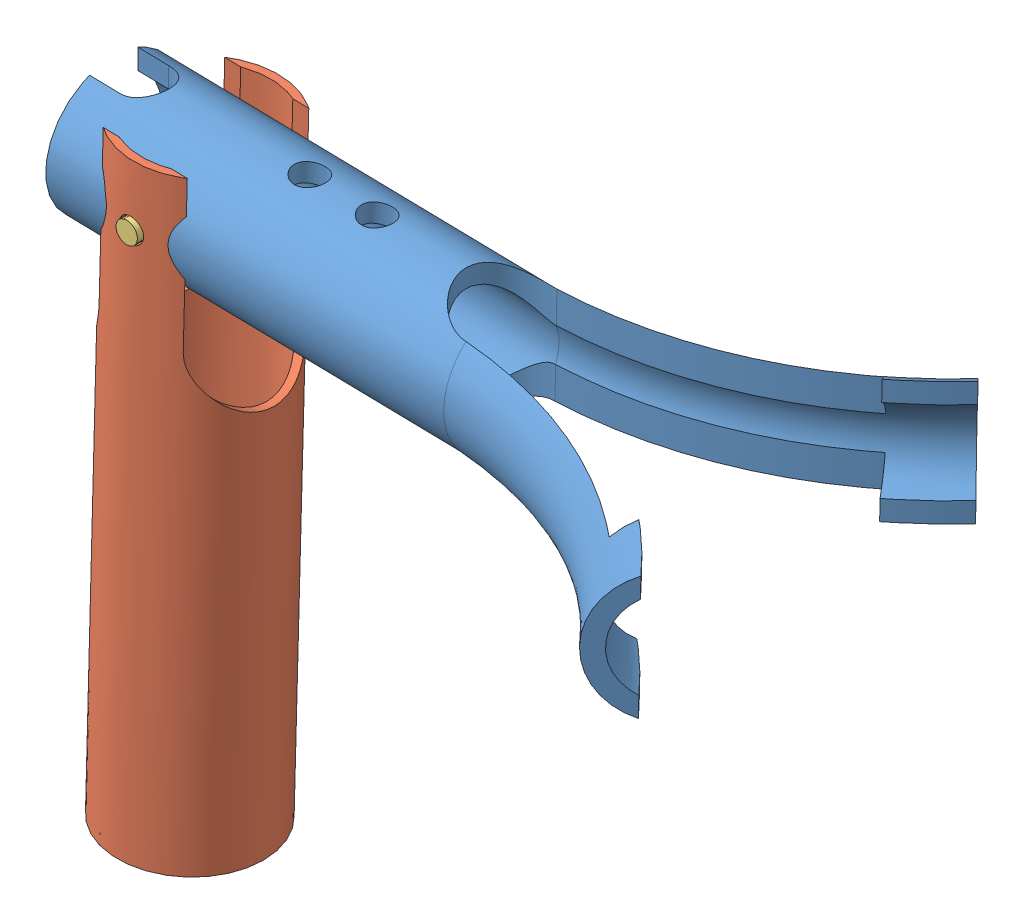
SolidWorks assembly pin joint assembly, configuration Default. Lengths in mm.
Overall size (19.69 24.55 21.3).
3 component instances, 3 part files, 8 mates.
Components (placement in the parent):
- tube-1: tube [Default] at (8.8823 0.7926 18.0506) x (0 0 -1) z (-0.019735 -0.999805 0) size (6.49 11.36 2.18)
- stainless steel tube_pin joint-1: stainless steel tube_pin joint [Default] at (10.4086 1.7627 18.0506) x (-0.026615 -0.999646 0) z (0.999646 -0.026615 0) size (11 2.41 2.41)
- pin-1: pin [Default] at (10.382 0.763 16.7795) x (0 0 1) z (-0.966111 0.258128 0) size (2.54 0.35 0.35)
Mates (geometry in assembly coordinates):
- Concentric1: concentric anti-aligned: circle of tube-1; circle of stainless steel tube_pin joint-1
- Concentric2: concentric: circle of tube-1; circle of stainless steel tube_pin joint-1
- Concentric3: concentric anti-aligned: circle of stainless steel tube_pin joint-1; circle of pin-1
- Coincident1: coincident anti-aligned: plane of tube-1; plane of stainless steel tube_pin joint-1
- Parallel1: parallel aligned: line of ? through (-35.1019 1.974 18.0506) axis (0.999646 -0.026615 0)
- Concentric4: concentric aligned: circle of tube-1; circle of stainless steel tube_pin joint-1
- Concentric7: concentric aligned: circle of tube-1; circle of stainless steel tube_pin joint-1
- Coincident3: coincident aligned: plane of tube-1; plane of stainless steel tube_pin joint-1
